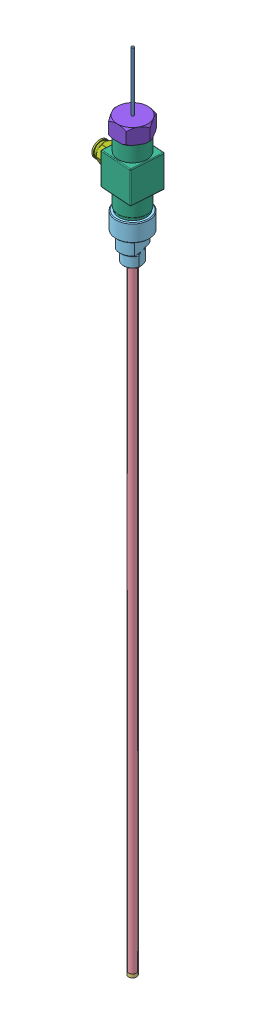
SolidWorks assembly Ensamblaje de Pipeta-Tee-Conectores-1, configuration Predeterminado. Lengths in mm.
Overall size (68.97 1003.7 49.84).
8 component instances, 8 part files, 12 mates.
Components (placement in the parent):
- Varilla de la pipeta-1: Varilla de la pipeta [Predeterminado] at (-128.4061 644.2501 1001.5875) size (3.17 1003.7 3.17)
- Buje interior del pico-1: Buje interior del pico [Predeterminado] at (-128.4061 -347.3121 1001.5875) x (0.891914 0 0.452205) z (-0.452205 0 0.891914) size (6 4 6)
- Pico de la Pipeta-1: Pico de la Pipeta [Predeterminado] at (-128.4061 -345.4376 1001.5875) x (0.169886 0 -0.985464) z (0.985464 0 0.169886) size (10 11 10)
- Pipeta-1: Pipeta [Predeterminado] at (-128.4061 -340.4376 1001.5875) x (0.182874 0 0.983136) z (-0.983136 0 0.182874) size (10 805 10)
- Buje Copa Superior-1: Buje Copa Superior [Predeterminado] at (-128.4061 425.5624 1001.5875) x (0.974575 0 -0.224063) z (0.224063 0 0.974575) size (41.58 56 41.58)
- Coneccion T de la Pipeta-1: Coneccion T de la Pipeta [Predeterminado] at (-128.4061 524.5624 1001.5875) x (0.997697 0 0.067828) z (-0.067828 0 0.997697) size (40 100 40)
- Conector Racor de Media G-1: Conector Racor de Media G [Predeterminado] at (-144.8924 524.5624 1000.4667) x (0.067661 -0.070187 -0.995237) z (0.997697 0 0.067828) size (26.56 20.78 32)
- Buje sello de Varilla-3: Buje sello de Varilla [Predeterminado] at (-128.4061 553.0977 1001.5875) size (48.39 37 38.11)
Mates (geometry in assembly coordinates):
- Concéntrica4: concentric aligned: cylinder of Varilla de la pipeta-1 through (-128.4061 655.5339 1001.5875) axis (0 1 0) radius 1.5875; cylinder of Buje interior del pico-1 through (-128.4061 -340.4258 1001.5875) axis (0 1 0) radius 3
- Concéntrica5: concentric aligned: cylinder of Buje interior del pico-1 through (-128.4061 -340.4258 1001.5875) axis (0 1 0) radius 3; cylinder of Pico de la Pipeta-1 through (-128.4061 -319.201 1001.5875) axis (0 1 0) radius 3
- Coincidente1: coincident anti-aligned: plane of Buje interior del pico-1 through (-127.2466 -344.4376 1002.1754) normal (0 -1 0); plane of Pico de la Pipeta-1 through (-127.8965 -344.4376 998.6311) normal (0 1 0)
- Concéntrica6: concentric anti-aligned: cylinder of Pico de la Pipeta-1 through (-128.4061 -319.201 1001.5875) axis (0 1 0) radius 4; cylinder of Pipeta-1 through (-128.4061 459.5624 1001.5875) axis (0 -1 0) radius 5
- Coincidente3: coincident anti-aligned: plane of Pico de la Pipeta-1 through (-127.5567 -340.4376 996.6602) normal (0 1 0); plane of Pipeta-1 through (-128.4061 -340.4376 1001.5875) normal (0 -1 0)
- Concéntrica7: concentric anti-aligned: cylinder of Pipeta-1 through (-128.4061 459.5624 1001.5875) axis (0 -1 0) radius 5; cylinder of Buje Copa Superior-1 through (-128.4061 475.9374 1001.5875) axis (0 1 0) radius 20.7902
- Coincidente4: coincident aligned: plane of Pipeta-1 through (-129.1376 464.5624 997.655) normal (0 1 0); plane of Buje Copa Superior-1 through (-123.2774 464.5624 1000.4084) normal (0 1 0)
- Concéntrica8: concentric anti-aligned: cylinder of Buje Copa Superior-1 through (-128.4061 475.9374 1001.5875) axis (0 1 0) radius 20.7902; cylinder of Coneccion T de la Pipeta-1 through (-128.4061 564.5624 1001.5875) axis (0 -1 0) radius 18
- Coincidente5: coincident anti-aligned: plane of Buje Copa Superior-1 through (-123.2774 464.5624 1000.4084) normal (0 1 0); plane of Coneccion T de la Pipeta-1 through (-128.4061 464.5624 1001.5875) normal (0 -1 0)
- Concéntrica10: concentric aligned: cylinder of Coneccion T de la Pipeta-1 through (-130.4015 524.5624 1001.4518) axis (-0.997697 0 -0.067828) radius 9.5; cylinder of Conector Racor de Media G-1 through (-179.7682 524.5624 998.0956) axis (-0.997697 0 -0.067828) radius 5
- Concéntrica11: concentric: cylinder of Coneccion T de la Pipeta-1 through (-128.4061 564.5624 1001.5875) axis (0 -1 0) radius 18; cylinder of Buje sello de Varilla-3 through (-128.4061 633.7899 1001.5875) axis (0 1 0) radius 17
- Coincidente6: coincident anti-aligned: plane of Coneccion T de la Pipeta-1 through (-128.4061 564.5624 1001.5875) normal (0 1 0); plane of Buje sello de Varilla-3 through (-111.4061 564.5624 1001.5875) normal (0 -1 0)
